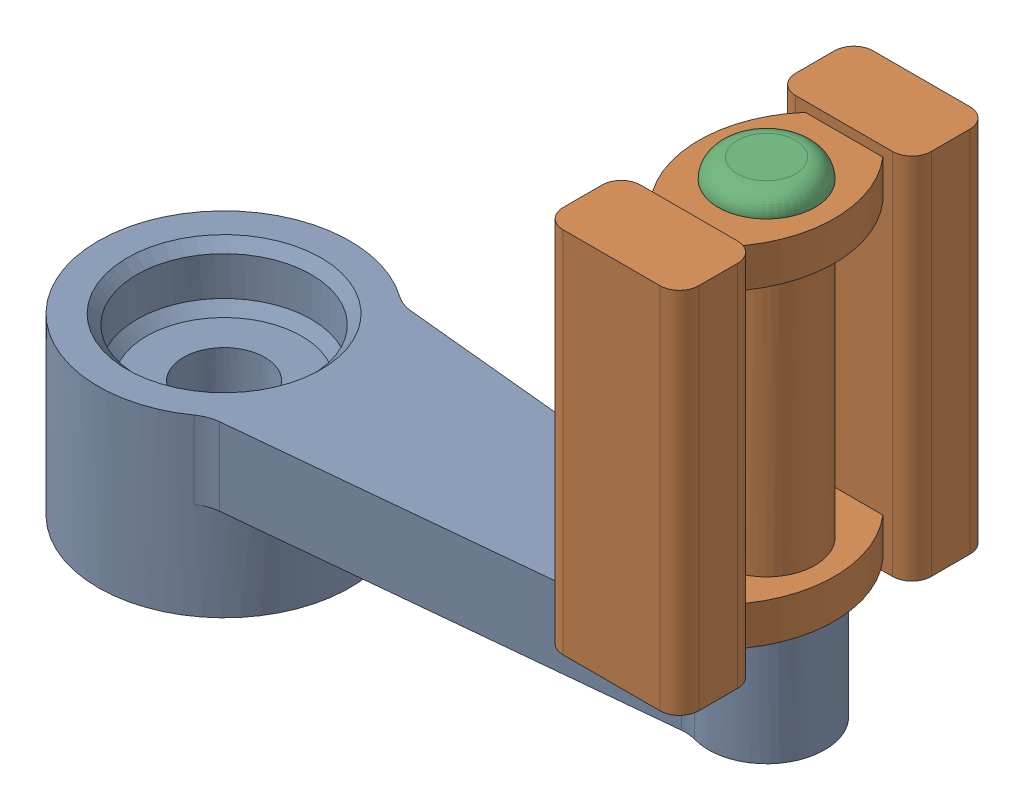
SolidWorks assembly Assem_Pedals, configuration Default. Lengths in mm.
Overall size (19 15 8).
3 component instances, 3 part files, 5 mates.
Components (placement in the parent):
- 13. pedal_axle-1: 13. pedal_axle [Default] at origin size (18.75 6 6.5)
- 12. pedal_foot-1: 12. pedal_foot [Default] at (14 6.5 0) x (0 0 -1) z (1 0 0) size (8 9.5 3.5)
- __pedal_pin-1: __pedal_pin [Default] at (14 10.5 0) x (0.128374 0 -0.991726) z (0.991726 0 0.128374) size (2.5 12 2.5)
Mates (geometry in assembly coordinates):
- Concentric1: concentric aligned: cylinder of Pedal_axle-1 through (14 1 0) axis (0 -1 0) radius 1.5; cylinder of Pedal_foot-1 through (14 11 0) axis (0 -1 0) radius 1.25
- Concentric2: concentric anti-aligned: cylinder of Pedal_foot-1 through (14 11 0) axis (0 -1 0) radius 1.25; cylinder of Pedal_pin-1 through (14 -0.5 0) axis (0 1 0) radius 1
- Coincident4: coincident aligned: circle of Accessories Pedal2-1; plane of Pedal_foot-1 through (14 2 0) normal (0 -1 0)
- Coincident5: coincident aligned: cone of Pedal_foot-1 through (14 10.75 0) axis (0 -1 0); cone of Pedal_pin-1 through (14 11 0) axis (0 -1 0)
- Parallel5: parallel aligned: plane of Pedal_axle-1 through (1.7321 0 0) normal (1 0 0); plane of Pedal_foot-1 through (15.75 11.25 -4) normal (1 0 0)
